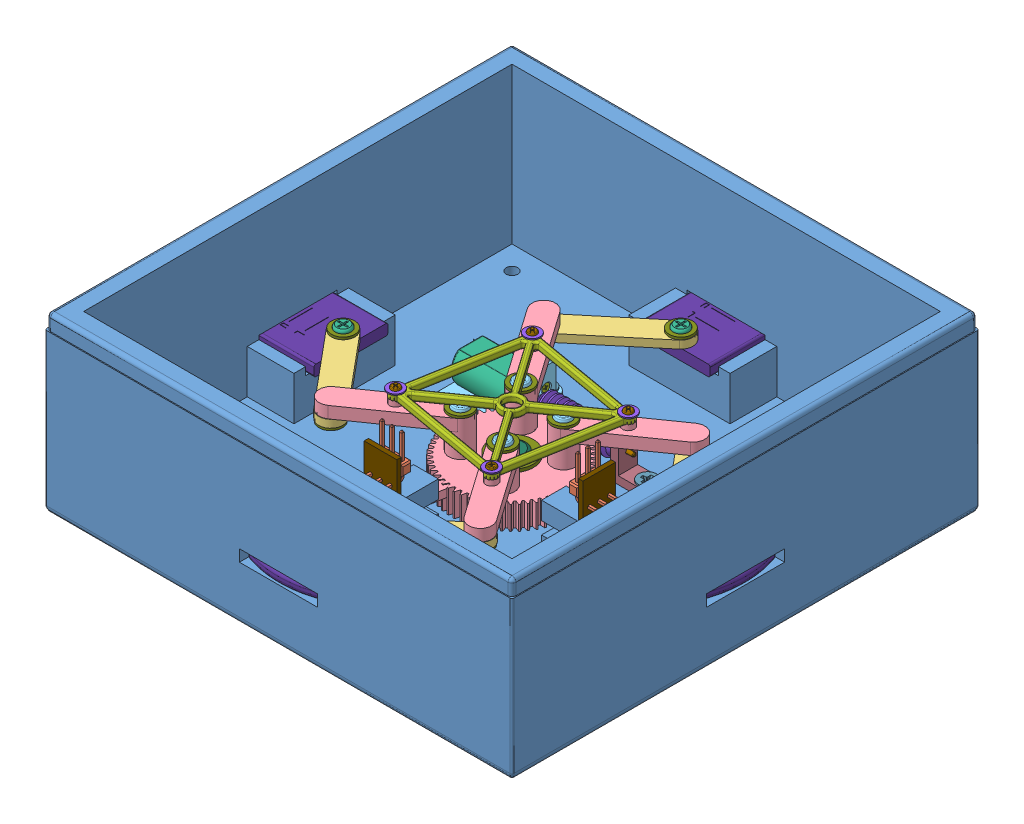
SolidWorks assembly Housing ASSY BOTTOM, configuration Default. Lengths in mm.
Overall size (120.15 45 120.15).
106 component instances, 28 part files, 150 mates.
Components (placement in the parent):
- Housing-Bottom-1: Housing-Bottom [Default] at (58.4375 46.7515 95.6927) size (120 45 120)
- HK 0606-1: HK 0606 [Default] at (58.4375 53.7515 95.6927) x (0 1 0) z (0 0 1) size (6 10 10)
  - HK 0606_PART1-1: HK 0606_PART1 [Default] at origin size (6 10 10)
  - HK 0606_PART2-1: HK 0606_PART2 [Default] at origin size (3.3 1.5 1.5)
  - HK 0606_PART2-2: HK 0606_PART2 [Default] x (1 0 0) z (0 0.707107 0.707107) size (3.3 1.5 1.5)
  - HK 0606_PART2-3: HK 0606_PART2 [Default] x (1 0 0) z (0 1 0) size (3.3 1.5 1.5)
  - HK 0606_PART2-4: HK 0606_PART2 [Default] x (1 0 0) z (0 0.707107 -0.707107) size (3.3 1.5 1.5)
  - HK 0606_PART2-5: HK 0606_PART2 [Default] x (1 0 0) z (0 0 -1) size (3.3 1.5 1.5)
  - HK 0606_PART2-6: HK 0606_PART2 [Default] x (1 0 0) z (0 -0.707107 -0.707107) size (3.3 1.5 1.5)
  - HK 0606_PART2-7: HK 0606_PART2 [Default] x (1 0 0) z (0 -1 0) size (3.3 1.5 1.5)
  - HK 0606_PART2-8: HK 0606_PART2 [Default] x (1 0 0) z (0 -0.707107 0.707107) size (3.3 1.5 1.5)
  - HK 0606_PART3-1: HK 0606_PART3 [Default] at origin
  - HK 0606_PART3-2: HK 0606_PART3 [Default] x (1 0 0) z (0 0.707107 0.707107)
  - HK 0606_PART3-3: HK 0606_PART3 [Default] x (1 0 0) z (0 1 0)
  - HK 0606_PART3-4: HK 0606_PART3 [Default] x (1 0 0) z (0 0.707107 -0.707107)
  - HK 0606_PART3-5: HK 0606_PART3 [Default] x (1 0 0) z (0 0 -1)
  - HK 0606_PART3-6: HK 0606_PART3 [Default] x (1 0 0) z (0 -0.707107 -0.707107)
  - HK 0606_PART3-7: HK 0606_PART3 [Default] x (1 0 0) z (0 -1 0)
  - HK 0606_PART3-8: HK 0606_PART3 [Default] x (1 0 0) z (0 -0.707107 0.707107)
- Center gear-1: Center gear [Default] at (58.4375 59.7515 95.6927) x (-0.818283 0 0.574815) z (0.574815 0 0.818283) size (37.48 15.12 34.22)
- Motor Stand ASSY-2: Motor Stand ASSY [Default] at (30.3718 47.9529 58.991) size (57.7 11.2 22)
  - Motor stand-1: Motor stand [Default] at (14.5557 9.9986 19.1017) x (0 -1 0) z (0 0 1) size (11.2 18.28 22)
  - PKN7EB105C motor-1: PKN7EB105C motor [Default] at (-0.4443 9.9986 19.1017) x (0 0 -1) z (0 -1 0) size (10 25.2 8)
  - SNZF-M1_4-3-TBZ-1: SNZF-M1_4-3-TBZ [Default] at (15.1057 9.9986 15.5017) x (-1 0 0) z (0 -0.147104 0.989121) size (3 2 2)
  - SNZF-M1_4-3-TBZ-2: SNZF-M1_4-3-TBZ [Default] at (15.1057 9.9986 22.7017) x (-1 0 0) z (0 -0.877398 0.479764) size (3 2 2)
  - Worm 21-1: Worm 21 [GearTrax] at (28.0557 9.9986 19.1017) x (0 0 -1) z (1 0 0) size (6 6 21.1)
  - 10mm shaft-1: 10mm shaft [Default] at (32.0557 9.9986 19.1017) x (0 0.407305 0.913292) z (1 0 0) size (1 1 10)
  - W 618_1-1: W 618_1 [Default] at (38.1557 9.9986 19.1017) size (1 3 3)
    - W 618_1_PART1-1: W 618_1_PART1 [Default] at origin size (1 1.55 1.55)
    - W 618_1_PART2-1: W 618_1_PART2 [Default] at origin size (1 3 3)
    - W 618_1_PART3-1: W 618_1_PART3 [Default] at origin size (0.6 0.6 0.6)
    - W 618_1_PART3-2: W 618_1_PART3 [Default] x (1 0 0) z (0 0.866025 0.5) size (0.6 0.6 0.6)
    - W 618_1_PART3-3: W 618_1_PART3 [Default] x (1 0 0) z (0 0.866025 -0.5) size (0.6 0.6 0.6)
    - W 618_1_PART3-4: W 618_1_PART3 [Default] x (1 0 0) z (0 0 -1) size (0.6 0.6 0.6)
    - W 618_1_PART3-5: W 618_1_PART3 [Default] x (1 0 0) z (0 -0.866025 -0.5) size (0.6 0.6 0.6)
    - W 618_1_PART3-6: W 618_1_PART3 [Default] x (1 0 0) z (0 -0.866025 0.5) size (0.6 0.6 0.6)
  - Bearing stand-2: Bearing stand [Default] at (40.2557 9.9986 19.1017) x (0 0 1) z (-1 0 0) size (5 8.7 17)
- countersunk flat head cross recess screw_iso-1: countersunk flat head cross recess screw_iso [ISO 7046-1 - M2.5 x 4 - Z - 4S] at (41.5775 53.9515 86.0927) x (0 -1 0) z (0.986483 0 -0.163866) size (4 4.7 4.7)
- countersunk flat head cross recess screw_iso-2: countersunk flat head cross recess screw_iso [ISO 7046-1 - M2.5 x 4 - Z - 4S] at (75.6275 54.2515 78.0927) x (0 -1 0) z (0.994864 0 -0.10122) size (4 4.7 4.7)
- countersunk flat head cross recess screw_iso-3: countersunk flat head cross recess screw_iso [ISO 7046-1 - M2.5 x 4 - Z - 4S] at (41.5775 53.9515 70.0927) x (0 -1 0) z (0.998701 0 -0.050963) size (4 4.7 4.7)
- countersunk flat head cross recess screw_iso-4: countersunk flat head cross recess screw_iso [ISO 7046-1 - M2.5 x 4 - Z - 4S] at (32.4775 53.9515 86.0927) x (0 -1 0) z (0 0 1) size (4 4.7 4.7)
- countersunk flat head cross recess screw_iso-5: countersunk flat head cross recess screw_iso [ISO 7046-1 - M2.5 x 4 - Z - 4S] at (32.4775 53.9515 70.0927) x (0 -1 0) z (-0.882562 0 0.470195) size (4 4.7 4.7)
- countersunk flat head cross recess screw_iso-6: countersunk flat head cross recess screw_iso [ISO 7046-1 - M2.5 x 4 - Z - 4S] at (80.6275 54.2515 78.0927) x (0 -1 0) z (0 0 1) size (4 4.7 4.7)
- SEQ-M3-6-TZB-1: SEQ-M3-6-TZB [Default] at (58.4375 60.5515 95.6927) x (0 -1 0) z (0 0 1) size (6.8 7 7)
- plain washer 10673 type snl_iso-4: plain washer 10673 type snl_iso [ISO 10673-3.2-L] at (58.4375 59.7515 95.6927) x (0 1 0) z (0.0196 0 -0.999808) size (0.8 11 11)
- Locking insert-1: Locking insert [Default] at (0.1058 63.8715 95.6927) x (1 0 0) z (0 -1 0) size (18.71 19 4.86)
- Locking insert-2: Locking insert [Default] at (58.4375 63.8715 37.3608) x (0 0 1) z (0 -1 0) size (18.71 19 4.86)
- Locking insert-3: Locking insert [Default] at (58.4375 63.8715 154.0246) x (0 0 -1) z (0 -1 0) size (18.71 19 4.86)
- Locking insert-4: Locking insert [Default] at (116.7696 63.8715 95.6927) x (-1 0 0) z (0 -1 0) size (18.71 19 4.86)
- LightInterrupter ASSY-1: LightInterrupter ASSY [Default] at (106.8605 54.653 115.9706) x (0 1 0) z (-1 0 0) size (27.79 23.15 13.77)
  - light interrupter-1: light interrupter [Default] at (-28.3605 -96.0125 19.17) size (23.5 8.4 2.42)
  - OPB840L51-1: OPB840L51 [Default] at (3.5735 12.3185 19.17) x (1 0 0) z (0 -1 0) size (12.95 13.04 23.15)
  - Pin Header 1x3 TH Angle Pitch 2.54mm-1: Pin Header 1x3 TH Angle Pitch 2.54mm [Default] at (14.0957 9.7707 19.1411) x (0 1 0) z (0 0 1) size (7.63 11.11 6.29)
- Lock lever 25-1: Lock lever 25 [Default] at (48.8375 63.8715 60.3329) x (-0.768003 0 0.640446) z (-0.640446 0 -0.768003) size (31.2 2 6.2)
- Lock lever 25-2: Lock lever 25 [Default] at (93.7975 63.8715 86.0927) x (-0.640452 0 -0.767999) z (0.767999 0 -0.640452) size (31.2 2 6.2)
- Lock lever 25-3: Lock lever 25 [Default] at (23.0778 63.8715 105.2928) x (-0.640443 0 -0.768006) z (0.768006 0 -0.640443) size (31.2 2 6.2)
- Lock lever 25-4: Lock lever 25 [Default] at (68.0376 63.8715 131.0525) x (0.768001 0 -0.640448) z (0.640448 0 0.768001) size (31.2 2 6.2)
- LightInterrupter ASSY-2: LightInterrupter ASSY [Default] at (43.6894 54.653 145.0604) x (0 1 0) z (0 0 -1) size (27.79 23.15 13.77)
  - light interrupter-1: light interrupter [Default] at (-28.3605 -96.0125 19.17) size (23.5 8.4 2.42)
  - OPB840L51-1: OPB840L51 [Default] at (3.5735 12.3185 19.17) x (1 0 0) z (0 -1 0) size (12.95 13.04 23.15)
  - Pin Header 1x3 TH Angle Pitch 2.54mm-1: Pin Header 1x3 TH Angle Pitch 2.54mm [Default] at (14.0957 9.7707 19.1411) x (0 1 0) z (0 0 1) size (7.63 11.11 6.29)
- Lock lever 23-1: Lock lever 23 [Default] at (40.8736 65.8715 108.0231) x (0.818582 0 -0.57439) z (0.57439 0 0.818582) size (29.92 12.12 6)
- Lock lever 23-2: Lock lever 23 [Default] at (70.7679 65.8715 113.2567) x (-0.574385 0 -0.818585) z (0.818585 0 -0.574385) size (29.92 12.12 6)
- Lock lever 23-3: Lock lever 23 [Default] at (76.0015 65.8715 83.3623) x (-0.818587 0 0.574382) z (-0.574382 0 -0.818587) size (29.92 12.12 6)
- Lock lever 23-4: Lock lever 23 [Default] at (46.1071 65.8715 78.1287) x (0.574387 0 0.818584) z (-0.818584 0 0.574387) size (29.92 12.12 6)
- plain washer 10673 type snl_iso-6: plain washer 10673 type snl_iso [ISO 10673-2.75-S] at (66.2112 68.8715 90.232) x (0 1 0) z (0 0 -1) size (0.6 6 6)
- plain washer 10673 type snl_iso-7: plain washer 10673 type snl_iso [ISO 10673-2.75-S] at (63.8983 68.8715 103.4664) x (0 1 0) z (0 0 -1) size (0.6 6 6)
- plain washer 10673 type snl_iso-8: plain washer 10673 type snl_iso [ISO 10673-2.75-S] at (50.6639 68.8715 101.1534) x (0 1 0) z (0 0 1) size (0.6 6 6)
- plain washer 10673 type snl_iso-9: plain washer 10673 type snl_iso [ISO 10673-2.75-S] at (52.9768 68.8715 87.919) x (0 1 0) z (0 0 1) size (0.6 6 6)
- SNZS-M2_5-6-1: SNZS-M2_5-6 [Default] at (50.6639 69.4715 101.1534) x (0 -1 0) z (0 0 1) size (6.8 4 4)
- SNZS-M2_5-6-2: SNZS-M2_5-6 [Default] at (63.8983 69.4715 103.4664) x (0 -1 0) z (0 0 1) size (6.8 4 4)
- SNZS-M2_5-6-3: SNZS-M2_5-6 [Default] at (52.9768 69.4715 87.919) x (0 -1 0) z (0 0 1) size (6.8 4 4)
- SNZS-M2_5-6-4: SNZS-M2_5-6 [Default] at (66.2112 69.4715 90.232) x (0 -1 0) z (0 0 1) size (6.8 4 4)
- plain washer 10673 type snl_iso-11: plain washer 10673 type snl_iso [ISO 10673-2.75-S] at (39.2375 63.8715 68.3385) x (0 -1 0) z (-0.982657 0 -0.185434) size (0.6 6 6)
- plain washer 10673 type snl_iso-13: plain washer 10673 type snl_iso [ISO 10673-2.75-S] at (77.6376 63.8715 123.0469) x (0 -1 0) z (-0.441249 0 -0.897385) size (0.6 6 6)
- plain washer 10673 type snl_iso-14: plain washer 10673 type snl_iso [ISO 10673-2.75-S] at (31.0834 63.8715 114.8928) x (0 -1 0) z (0 0 1) size (0.6 6 6)
- plain washer 10673 type snl_iso-16: plain washer 10673 type snl_iso [ISO 10673-2.75-S] at (85.7918 63.8715 76.4927) x (0 -1 0) z (0.546944 0 -0.837169) size (0.6 6 6)
- SNZS-M2_5-3-1: SNZS-M2_5-3 [Default] at (77.6376 63.2715 123.0469) x (0 1 0) z (0 0 1) size (3.8 4.02 4.02)
- SNZS-M2_5-3-2: SNZS-M2_5-3 [Default] at (31.0834 63.2715 114.8928) x (0 1 0) z (0 0 1) size (3.8 4.02 4.02)
- SNZS-M2_5-3-3: SNZS-M2_5-3 [Default] at (85.7918 63.2715 76.4927) x (0 1 0) z (0 0 1) size (3.8 4.02 4.02)
- SNZS-M2_5-3-4: SNZS-M2_5-3 [Default] at (39.2375 63.2715 68.3385) x (0 1 0) z (0 0 1) size (3.8 4.02 4.02)
- plain washer 10673 type snl_iso-18: plain washer 10673 type snl_iso [ISO 10673-2.75-S] at (58.4375 65.8715 52.3273) x (0 1 0) z (0 0 1) size (0.6 6 6)
- plain washer 10673 type snl_iso-19: plain washer 10673 type snl_iso [ISO 10673-2.75-S] at (15.0723 65.8715 95.6927) x (0 1 0) z (0 0 1) size (0.6 6 6)
- plain washer 10673 type snl_iso-20: plain washer 10673 type snl_iso [ISO 10673-2.75-S] at (58.4375 65.8715 139.0582) x (0 1 0) z (0 0 1) size (0.6 6 6)
- plain washer 10673 type snl_iso-21: plain washer 10673 type snl_iso [ISO 10673-2.75-S] at (101.8031 65.8715 95.6927) x (0 1 0) z (-0.915769 0 0.401704) size (0.6 6 6)
- SNZS-M2_5-3-5: SNZS-M2_5-3 [Default] at (15.0723 66.4715 95.6927) x (0 -1 0) z (0 0 1) size (3.8 4.02 4.02)
- SNZS-M2_5-3-6: SNZS-M2_5-3 [Default] at (58.4375 66.4715 52.3273) x (0 -1 0) z (0 0 1) size (3.8 4.02 4.02)
- SNZS-M2_5-3-7: SNZS-M2_5-3 [Default] at (101.8031 66.4715 95.6927) x (0 -1 0) z (0 0 1) size (3.8 4.02 4.02)
- SNZS-M2_5-3-8: SNZS-M2_5-3 [Default] at (58.4375 66.4715 139.0582) x (0 -1 0) z (0 0 1) size (3.8 4.02 4.02)
- 23 lever spacer-2: 23 lever spacer [Default] at (58.4376 69.8715 95.6927) x (0.985019 0 0.172446) z (-0.172446 0 0.985019) size (33.35 2.06 33.35)
- plain washer normal grade a_iso-2: plain washer normal grade a_iso [Washer ISO 7089 - 1.6] at (46.1071 71.8715 78.1287) x (0 -1 0) z (0.996822 0 0.079656) size (0.3 4 4)
- plain washer normal grade a_iso-3: plain washer normal grade a_iso [Washer ISO 7089 - 1.6] at (40.873 71.8715 108.0235) x (0 -1 0) z (0.445519 0 -0.895272) size (0.3 4 4)
- plain washer normal grade a_iso-4: plain washer normal grade a_iso [Washer ISO 7089 - 1.6] at (70.7679 71.8715 113.2567) x (0 -1 0) z (0 0 1) size (0.3 4 4)
- plain washer normal grade a_iso-5: plain washer normal grade a_iso [Washer ISO 7089 - 1.6] at (76.0015 71.8715 83.3623) x (0 -1 0) z (0 0 1) size (0.3 4 4)
- SNZS-M1_6-3-5: SNZS-M1_6-3 [Default] at (76.0015 72.1715 83.3623) x (0 -1 0) z (0 0 1) size (3.5 2.3 2.3)
- SNZS-M1_6-3-6: SNZS-M1_6-3 [Default] at (70.7679 72.1715 113.2567) x (0 -1 0) z (-0.649279 0 0.76055) size (3.5 2.3 2.3)
- SNZS-M1_6-3-7: SNZS-M1_6-3 [Default] at (46.1071 72.1715 78.1287) x (0 -1 0) z (0 0 1) size (3.5 2.3 2.3)
- SNZS-M1_6-3-8: SNZS-M1_6-3 [Default] at (40.8736 72.1715 108.0231) x (0 -1 0) z (0 0 1) size (3.5 2.3 2.3)
- plain washer normal grade a_iso-10: plain washer normal grade a_iso [Washer ISO 7089 - 1.6] at (81.7255 53.7815 110.7622) x (0 -1 0) z (0.705829 0 0.708382) size (0.3 4 4)
- plain washer normal grade a_iso-11: plain washer normal grade a_iso [Washer ISO 7089 - 1.6] at (48.8979 53.7815 119.9254) x (0 -1 0) z (0 0 1) size (0.3 4 4)
- plain washer normal grade a_iso-12: plain washer normal grade a_iso [Washer ISO 7089 - 1.6] at (81.7255 53.7815 96.546) x (0 -1 0) z (0 0 1) size (0.3 4 4)
- plain washer normal grade a_iso-13: plain washer normal grade a_iso [Washer ISO 7089 - 1.6] at (63.114 53.7815 119.9254) x (0 -1 0) z (0 0 1) size (0.3 4 4)
- SNZS-M1_6-3-9: SNZS-M1_6-3 [Default] at (48.8979 54.0815 119.9254) x (0 -1 0) z (1 0 0) size (3.5 2.3 2.3)
- SNZS-M1_6-3-10: SNZS-M1_6-3 [Default] at (81.7255 54.0815 96.546) x (0 -1 0) z (0 0 1) size (3.5 2.3 2.3)
- SNZS-M1_6-3-11: SNZS-M1_6-3 [Default] at (81.7255 54.0815 110.7622) x (0 -1 0) z (0 0 1) size (3.5 2.3 2.3)
- SNZS-M1_6-3-12: SNZS-M1_6-3 [Default] at (63.114 54.0815 119.9254) x (0 -1 0) z (0 0 1) size (3.5 2.3 2.3)
Mates (geometry in assembly coordinates):
- Concentric1: concentric anti-aligned: circle of Housing-Bottom-1; circle of HK 0606-1/HK 0606_PART1-1
- Coincident3: coincident anti-aligned: plane of Housing-Bottom-1 through (58.4375 53.7515 95.6927) normal (0 1 0); plane of HK 0606-1/HK 0606_PART1-1 through (53.8375 53.7515 95.6927) normal (0 -1 0)
- Concentric2: concentric aligned: circle of HK 0606-1/HK 0606_PART1-1; circle of Center gear-1
- Coincident4: coincident anti-aligned: plane of Housing-Bottom-1 through (58.4375 53.7515 95.6927) normal (0 1 0); plane of Center gear-1 through (57.2231 53.7515 88.7504) normal (0 -1 0)
- Coincident5: coincident anti-aligned: plane of Housing-Bottom-1 through (58.4375 51.7515 95.6927) normal (0 1 0); plane of Motor Stand ASSY-2/Motor stand-1 through (32.4775 51.7515 70.0927) normal (0 -1 0)
- Concentric4: concentric anti-aligned: circle of Housing-Bottom-1; circle of Motor Stand ASSY-2/Motor stand-1
- Concentric5: concentric anti-aligned: circle of Housing-Bottom-1; circle of Motor Stand ASSY-2/Motor stand-1
- Concentric6: concentric aligned: circle of Housing-Bottom-1; circle of countersunk flat head cross recess screw_iso-6
- Coincident6: coincident aligned: cone of Motor Stand ASSY-2/Bearing stand-2 through (80.6275 52.7515 78.0927) axis (0 -1 0); cylinder of countersunk flat head cross recess screw_iso-6 through (80.6275 53.8515 78.0927) axis (0 -1 0) radius 785.3982
- Concentric7: concentric aligned: circle of Motor Stand ASSY-2/Bearing stand-2; cylinder of countersunk flat head cross recess screw_iso-2 through (75.6275 60.6015 78.0927) axis (0 1 0) radius 1.25
- Coincident9: coincident aligned: cylinder of Motor Stand ASSY-2/Bearing stand-2 through (75.6275 52.7515 78.0927) axis (0 -1 0) radius 785.3982; cylinder of countersunk flat head cross recess screw_iso-2 through (75.6275 53.8515 78.0927) axis (0 -1 0) radius 785.3982
- Concentric8: concentric anti-aligned: circle of Housing-Bottom-1; cylinder of countersunk flat head cross recess screw_iso-4 through (32.4775 49.9515 86.0927) axis (0 -1 0) radius 959.9311
- Coincident11: coincident aligned: cylinder of Motor Stand ASSY-2/Motor stand-1 through (32.4775 52.4515 86.0927) axis (0 -1 0) radius 785.3982; cylinder of countersunk flat head cross recess screw_iso-4 through (32.4775 53.5515 86.0927) axis (0 -1 0) radius 785.3982
- Concentric9: concentric aligned: circle of Housing-Bottom-1; circle of countersunk flat head cross recess screw_iso-5
- Coincident12: coincident aligned: cylinder of Motor Stand ASSY-2/Motor stand-1 through (32.4775 52.9515 70.0927) axis (0 -1 0) radius 785.3982; cylinder of countersunk flat head cross recess screw_iso-5 through (32.4775 53.5515 70.0927) axis (0 -1 0) radius 785.3982
- Concentric10: concentric aligned: circle of Housing-Bottom-1; circle of countersunk flat head cross recess screw_iso-3
- Coincident13: coincident aligned: cylinder of Motor Stand ASSY-2/Motor stand-1 through (41.5775 52.9515 70.0927) axis (0 -1 0) radius 785.3982; cylinder of countersunk flat head cross recess screw_iso-3 through (41.5775 53.5515 70.0927) axis (0 -1 0) radius 785.3982
- Concentric11: concentric aligned: circle of Housing-Bottom-1; circle of countersunk flat head cross recess screw_iso-1
- Coincident14: coincident aligned: cylinder of Motor Stand ASSY-2/Motor stand-1 through (41.5775 52.4515 86.0927) axis (0 -1 0) radius 785.3982; cylinder of countersunk flat head cross recess screw_iso-1 through (41.5775 53.5515 86.0927) axis (0 -1 0) radius 785.3982
- Concentric12: concentric anti-aligned: cylinder of Housing-Bottom-1 through (58.4375 59.7515 95.6927) axis (0 -1 0) radius 3; cylinder of ? through (58.4375 87.5515 95.6927) axis (0 1 0) radius 2.8
- Coincident15: coincident: plane of Housing-Bottom-1 through (58.4375 59.7515 95.6927) normal (0 1 0); plane of ? through (59.9375 59.7515 95.6927) normal (0 -1 0)
- Concentric14: concentric aligned: cylinder of Housing-Bottom-1 through (58.4375 59.7515 95.6927) axis (0 -1 0) radius 3; cylinder of ? through (58.4375 60.5515 95.6927) axis (0 -1 0) radius 1.6
- Coincident19: coincident anti-aligned: plane of Housing-Bottom-1 through (58.4375 59.7515 95.6927) normal (0 1 0); plane of plain washer 10673 type snl_iso-4 through (58.4375 59.7515 95.6927) normal (0 -1 0)
- Concentric15: concentric anti-aligned: cylinder of Housing-Bottom-1 through (58.4375 51.7515 95.6927) axis (0 1 0) radius 1.2; cylinder of plain washer 10673 type snl_iso-4 through (58.4375 60.5515 95.6927) axis (0 -1 0) radius 1.6
- Coincident20: coincident anti-aligned: plane of Housing-Bottom-1 through (58.4375 59.7515 95.6927) normal (0 1 0); plane of plain washer 10673 type snl_iso-4 through (58.4375 59.7515 95.6927) normal (0 -1 0)
- Concentric16: concentric aligned: circle of SEQ-M3-6-TZB-1; circle of plain washer 10673 type snl_iso-4
- Coincident21: coincident aligned: circle of SEQ-M3-6-TZB-1; plane of plain washer 10673 type snl_iso-4 through (58.4375 60.5515 95.6927) normal (0 1 0)
- Distance3: distance = 0.1 mm anti-aligned: plane of Locking insert-3 through (58.4375 63.8715 129.0246) normal (0 1 0); plane of Housing-Bottom-1 through (48.4375 63.9715 155.6927) normal (0 -1 0)
- Distance5: distance = 0.5 mm anti-aligned: plane of Locking insert-3 through (67.9375 61.0715 137.0582) normal (1 0 0); plane of Housing-Bottom-1 through (68.4375 63.9715 155.6927) normal (-1 0 0)
- Distance6: distance = 0.5 mm anti-aligned: plane of Housing-Bottom-1 through (-1.5625 63.9715 105.6927) normal (0 0 -1); plane of Locking insert-1 through (17.0723 61.0715 105.1927) normal (0 0 1)
- Distance7: distance = 0.1 mm anti-aligned: plane of Housing-Bottom-1 through (-1.5625 60.9715 105.6927) normal (0 1 0); plane of Locking insert-1 through (25.1058 61.0715 95.6927) normal (0 -1 0)
- Distance8: distance = 0.5 mm anti-aligned: plane of Locking insert-2 through (48.9375 61.0715 54.3273) normal (-1 0 0); plane of Housing-Bottom-1 through (48.4375 63.9715 35.6927) normal (1 0 0)
- Distance9: distance = 0.1 mm anti-aligned: plane of Locking insert-2 through (58.4375 61.0715 62.3608) normal (0 -1 0); plane of Housing-Bottom-1 through (48.4375 60.9715 35.6927) normal (0 1 0)
- Distance10: distance = 0.1 mm anti-aligned: plane of Locking insert-4 through (91.7696 61.0715 95.6927) normal (0 -1 0); plane of Housing-Bottom-1 through (118.4375 60.9715 85.6927) normal (0 1 0)
- Distance11: distance = 0.5 mm anti-aligned: plane of Locking insert-4 through (99.8031 61.0715 86.1927) normal (0 0 -1); plane of Housing-Bottom-1 through (118.4375 63.9715 85.6927) normal (0 0 1)
- Concentric18: concentric aligned: circle of Locking insert-3; circle of Lock lever 25-4
- Concentric19: concentric aligned: circle of Locking insert-4; circle of Lock lever 25-2
- Concentric20: concentric aligned: circle of Locking insert-2; circle of Lock lever 25-1
- Concentric21: concentric aligned: circle of Locking insert-1; circle of Lock lever 25-3
- Coincident38: coincident anti-aligned: plane of Locking insert-2 through (58.4375 63.8715 62.3608) normal (0 1 0); plane of Lock lever 25-1 through (58.4375 63.8715 52.3273) normal (0 -1 0)
- Coincident39: coincident anti-aligned: plane of Locking insert-1 through (25.1058 63.8715 95.6927) normal (0 1 0); plane of Lock lever 25-3 through (31.0834 63.8715 114.8928) normal (0 -1 0)
- Coincident40: coincident anti-aligned: plane of Locking insert-3 through (58.4375 63.8715 129.0246) normal (0 1 0); plane of Lock lever 25-4 through (58.4375 63.8715 139.0582) normal (0 -1 0)
- Coincident41: coincident anti-aligned: plane of Locking insert-4 through (91.7696 63.8715 95.6927) normal (0 1 0); plane of Lock lever 25-2 through (101.8031 63.8715 95.6927) normal (0 -1 0)
- Concentric22: concentric anti-aligned: circle of Center gear-1; circle of Lock lever 23-1
- Concentric23: concentric anti-aligned: circle of Lock lever 25-3; circle of Lock lever 23-1
- Coincident43: coincident anti-aligned: plane of Lock lever 25-3 through (31.0834 65.8715 114.8928) normal (0 1 0); plane of Lock lever 23-1 through (31.0834 65.8715 114.8928) normal (0 -1 0)
- Concentric24: concentric anti-aligned: circle of Center gear-1; circle of Lock lever 23-3
- Concentric25: concentric anti-aligned: circle of Lock lever 25-2; circle of Lock lever 23-3
- Coincident45: coincident anti-aligned: plane of Lock lever 25-2 through (101.8031 65.8715 95.6927) normal (0 1 0); plane of Lock lever 23-3 through (85.7918 65.8715 76.4927) normal (0 -1 0)
- Concentric26: concentric anti-aligned: circle of Lock lever 25-4; circle of Lock lever 23-2
- Concentric27: concentric anti-aligned: circle of Center gear-1; circle of Lock lever 23-2
- Coincident46: coincident anti-aligned: plane of Lock lever 25-4 through (58.4375 65.8715 139.0582) normal (0 1 0); plane of Lock lever 23-2 through (77.6376 65.8715 123.0469) normal (0 -1 0)
- Concentric28: concentric anti-aligned: circle of Lock lever 25-1; circle of Lock lever 23-4
- Concentric29: concentric anti-aligned: circle of Center gear-1; circle of Lock lever 23-4
- Coincident47: coincident anti-aligned: plane of Lock lever 25-1 through (58.4375 65.8715 52.3273) normal (0 1 0); plane of Lock lever 23-4 through (39.2375 65.8715 68.3385) normal (0 -1 0)
- Concentric30: concentric aligned: circle of Lock lever 23-2; circle of ?
- Concentric31: concentric aligned: circle of Lock lever 23-1; circle of ?
- Concentric32: concentric aligned: circle of Lock lever 23-3; circle of ?
- Concentric33: concentric aligned: circle of Lock lever 23-4; circle of ?
- Concentric34: concentric anti-aligned: cylinder of Center gear-1 through (66.2112 60.8715 90.232) axis (0 1 0) radius 1.1; cylinder of plain washer 10673 type snl_iso-6 through (66.2112 69.4715 90.232) axis (0 -1 0) radius 1.375
- Coincident54: coincident anti-aligned: plane of Center gear-1 through (66.2112 68.8715 90.232) normal (0 1 0); plane of plain washer 10673 type snl_iso-6 through (66.2112 68.8715 90.232) normal (0 -1 0)
- Concentric35: concentric aligned: cylinder of Lock lever 23-2 through (63.8983 68.8715 103.4664) axis (0 -1 0) radius 2.1; cylinder of plain washer 10673 type snl_iso-7 through (63.8983 69.4715 103.4664) axis (0 -1 0) radius 1.375
- Coincident55: coincident anti-aligned: plane of Lock lever 23-2 through (77.6376 68.8715 123.0469) normal (0 1 0); plane of plain washer 10673 type snl_iso-7 through (63.8983 68.8715 103.4664) normal (0 -1 0)
- Concentric36: concentric anti-aligned: cylinder of Center gear-1 through (50.6639 60.8715 101.1534) axis (0 1 0) radius 1.1; cylinder of plain washer 10673 type snl_iso-8 through (50.6639 69.4715 101.1534) axis (0 -1 0) radius 1.375
- Coincident56: coincident anti-aligned: plane of Center gear-1 through (50.6639 68.8715 101.1534) normal (0 1 0); plane of plain washer 10673 type snl_iso-8 through (50.6639 68.8715 101.1534) normal (0 -1 0)
- Concentric37: concentric anti-aligned: cylinder of Center gear-1 through (52.9768 60.8715 87.919) axis (0 1 0) radius 1.1; cylinder of plain washer 10673 type snl_iso-9 through (52.9768 69.4715 87.919) axis (0 -1 0) radius 1.375
- Coincident57: coincident anti-aligned: plane of Center gear-1 through (52.9768 68.8715 87.919) normal (0 1 0); plane of plain washer 10673 type snl_iso-9 through (52.9768 68.8715 87.919) normal (0 -1 0)
- Concentric38: concentric aligned: circle of Center gear-1; circle of SNZS-M2_5-6-4
- Coincident58: coincident anti-aligned: plane of plain washer 10673 type snl_iso-6 through (66.2112 69.4715 90.232) normal (0 1 0); plane of SNZS-M2_5-6-4 through (68.2112 69.4715 90.232) normal (0 -1 0)
- Concentric39: concentric aligned: circle of Center gear-1; circle of SNZS-M2_5-6-2
- Coincident59: coincident anti-aligned: plane of plain washer 10673 type snl_iso-7 through (63.8983 69.4715 103.4664) normal (0 1 0); plane of SNZS-M2_5-6-2 through (65.8983 69.4715 103.4664) normal (0 -1 0)
- Concentric40: concentric aligned: circle of Center gear-1; circle of SNZS-M2_5-6-1
- Coincident60: coincident anti-aligned: plane of plain washer 10673 type snl_iso-8 through (50.6639 69.4715 101.1534) normal (0 1 0); plane of SNZS-M2_5-6-1 through (52.6639 69.4715 101.1534) normal (0 -1 0)
- Concentric41: concentric aligned: circle of Center gear-1; circle of SNZS-M2_5-6-3
- Coincident61: coincident anti-aligned: plane of plain washer 10673 type snl_iso-9 through (52.9768 69.4715 87.919) normal (0 1 0); plane of SNZS-M2_5-6-3 through (54.9768 69.4715 87.919) normal (0 -1 0)
- Concentric42: concentric anti-aligned: cylinder of Lock lever 23-4 through (39.2375 67.3715 68.3385) axis (0 -1 0) radius 1.1; cylinder of plain washer 10673 type snl_iso-11 through (39.2375 63.2715 68.3385) axis (0 1 0) radius 1.375
- Coincident62: coincident anti-aligned: plane of Lock lever 23-4 through (39.2375 63.8715 68.3385) normal (0 -1 0); plane of plain washer 10673 type snl_iso-11 through (39.2375 63.8715 68.3385) normal (0 1 0)
- Concentric43: concentric anti-aligned: cylinder of Lock lever 23-2 through (77.6376 67.3715 123.0469) axis (0 -1 0) radius 1.1; cylinder of plain washer 10673 type snl_iso-13 through (77.6376 63.2715 123.0469) axis (0 1 0) radius 1.375
- Coincident63: coincident anti-aligned: plane of Lock lever 23-2 through (77.6376 63.8715 123.0469) normal (0 -1 0); plane of plain washer 10673 type snl_iso-13 through (77.6376 63.8715 123.0469) normal (0 1 0)
- Concentric44: concentric anti-aligned: cylinder of Lock lever 23-1 through (31.0834 67.3715 114.8928) axis (0 -1 0) radius 1.1; cylinder of plain washer 10673 type snl_iso-14 through (31.0834 63.2715 114.8928) axis (0 1 0) radius 1.375
- Coincident64: coincident anti-aligned: plane of Lock lever 23-1 through (31.0834 63.8715 114.8928) normal (0 -1 0); plane of plain washer 10673 type snl_iso-14 through (31.0834 63.8715 114.8928) normal (0 1 0)
- Concentric45: concentric anti-aligned: cylinder of Lock lever 23-3 through (85.7918 67.3715 76.4927) axis (0 -1 0) radius 1.1; cylinder of plain washer 10673 type snl_iso-16 through (85.7918 63.2715 76.4927) axis (0 1 0) radius 1.375
- Coincident65: coincident anti-aligned: plane of Lock lever 23-3 through (85.7918 63.8715 76.4927) normal (0 -1 0); plane of plain washer 10673 type snl_iso-16 through (85.7918 63.8715 76.4927) normal (0 1 0)
- Concentric46: concentric aligned: circle of Lock lever 23-4; circle of SNZS-M2_5-3-4
- Coincident66: coincident anti-aligned: plane of plain washer 10673 type snl_iso-11 through (39.2375 63.2715 68.3385) normal (0 -1 0); plane of SNZS-M2_5-3-4 through (37.2375 63.2715 68.3385) normal (0 1 0)
- Concentric47: concentric aligned: circle of Lock lever 23-1; circle of SNZS-M2_5-3-2
- Coincident67: coincident anti-aligned: plane of plain washer 10673 type snl_iso-14 through (31.0834 63.2715 114.8928) normal (0 -1 0); plane of SNZS-M2_5-3-2 through (29.0834 63.2715 114.8928) normal (0 1 0)
- Concentric48: concentric aligned: circle of Lock lever 23-2; circle of SNZS-M2_5-3-1
- Coincident68: coincident anti-aligned: plane of plain washer 10673 type snl_iso-13 through (77.6376 63.2715 123.0469) normal (0 -1 0); plane of SNZS-M2_5-3-1 through (75.6376 63.2715 123.0469) normal (0 1 0)
- Concentric49: concentric aligned: circle of Lock lever 23-3; circle of SNZS-M2_5-3-3
- Coincident69: coincident anti-aligned: plane of plain washer 10673 type snl_iso-16 through (85.7918 63.2715 76.4927) normal (0 -1 0); plane of SNZS-M2_5-3-3 through (83.7918 63.2715 76.4927) normal (0 1 0)
- Concentric50: concentric anti-aligned: cylinder of Locking insert-2 through (58.4375 62.3715 52.3273) axis (0 1 0) radius 1.1; cylinder of plain washer 10673 type snl_iso-18 through (58.4375 66.4715 52.3273) axis (0 -1 0) radius 1.375
- Coincident70: coincident anti-aligned: plane of Locking insert-2 through (58.4375 65.8715 52.3273) normal (0 1 0); plane of plain washer 10673 type snl_iso-18 through (58.4375 65.8715 52.3273) normal (0 -1 0)
- Concentric51: concentric aligned: cylinder of Locking insert-1 through (15.0723 65.8715 95.6927) axis (0 -1 0) radius 2; cylinder of plain washer 10673 type snl_iso-19 through (15.0723 66.4715 95.6927) axis (0 -1 0) radius 1.375
- Coincident71: coincident anti-aligned: plane of Locking insert-1 through (15.0723 65.8715 95.6927) normal (0 1 0); plane of plain washer 10673 type snl_iso-19 through (15.0723 65.8715 95.6927) normal (0 -1 0)
- Concentric52: concentric aligned: cylinder of Lock lever 25-4 through (58.4375 65.8715 139.0582) axis (0 -1 0) radius 2.1; cylinder of plain washer 10673 type snl_iso-20 through (58.4375 66.4715 139.0582) axis (0 -1 0) radius 1.375
- Coincident72: coincident anti-aligned: plane of Lock lever 25-4 through (58.4375 65.8715 139.0582) normal (0 1 0); plane of plain washer 10673 type snl_iso-20 through (58.4375 65.8715 139.0582) normal (0 -1 0)
- Concentric53: concentric aligned: cylinder of Lock lever 25-2 through (101.8031 65.8715 95.6927) axis (0 -1 0) radius 2.1; cylinder of plain washer 10673 type snl_iso-21 through (101.8031 66.4715 95.6927) axis (0 -1 0) radius 1.375
- Coincident73: coincident anti-aligned: plane of Lock lever 25-2 through (101.8031 65.8715 95.6927) normal (0 1 0); plane of plain washer 10673 type snl_iso-21 through (101.8031 65.8715 95.6927) normal (0 -1 0)
- Concentric54: concentric aligned: circle of Locking insert-2; circle of SNZS-M2_5-3-6
- Coincident74: coincident anti-aligned: plane of plain washer 10673 type snl_iso-18 through (58.4375 66.4715 52.3273) normal (0 1 0); plane of SNZS-M2_5-3-6 through (60.4375 66.4715 52.3273) normal (0 -1 0)
- Concentric55: concentric aligned: circle of Locking insert-1; circle of SNZS-M2_5-3-5
- Coincident75: coincident anti-aligned: plane of plain washer 10673 type snl_iso-19 through (15.0723 66.4715 95.6927) normal (0 1 0); plane of SNZS-M2_5-3-5 through (17.0723 66.4715 95.6927) normal (0 -1 0)
- Concentric56: concentric aligned: circle of Locking insert-3; circle of SNZS-M2_5-3-8
- Coincident76: coincident anti-aligned: plane of plain washer 10673 type snl_iso-20 through (58.4375 66.4715 139.0582) normal (0 1 0); plane of SNZS-M2_5-3-8 through (60.4375 66.4715 139.0582) normal (0 -1 0)
- Concentric57: concentric aligned: circle of Locking insert-4; circle of SNZS-M2_5-3-7
- Coincident77: coincident anti-aligned: plane of plain washer 10673 type snl_iso-21 through (101.8031 66.4715 95.6927) normal (0 1 0); plane of SNZS-M2_5-3-7 through (103.8031 66.4715 95.6927) normal (0 -1 0)
- Concentric58: concentric aligned: circle of Lock lever 23-2; circle of 23 lever spacer-2
- Concentric59: concentric aligned: circle of Lock lever 23-3; circle of 23 lever spacer-2
- Concentric60: concentric aligned: circle of Lock lever 23-4; circle of 23 lever spacer-2
- Concentric63: concentric aligned: circle of Lock lever 23-1; circle of 23 lever spacer-2
- Coincident78: coincident anti-aligned: plane of Lock lever 23-3 through (76.0015 70.8715 83.3623) normal (0 1 0); plane of 23 lever spacer-2 through (76.0021 70.8715 83.362) normal (0 -1 0)
- Concentric64: concentric aligned: cylinder of Lock lever 23-4 through (46.1071 68.3715 78.1287) axis (0 1 0) radius 0.625; cylinder of plain washer normal grade a_iso-2 through (46.1071 106.7965 78.1287) axis (0 1 0) radius 0.85
- Coincident79: coincident anti-aligned: plane of Lock lever 23-4 through (46.1071 71.8715 78.1287) normal (0 1 0); plane of plain washer normal grade a_iso-2 through (46.1748 71.8715 77.2814) normal (0 -1 0)
- Concentric65: concentric aligned: cylinder of 23 lever spacer-2 through (40.873 69.8715 108.0235) axis (0 1 0) radius 0.8; cylinder of plain washer normal grade a_iso-3 through (40.873 106.7965 108.0235) axis (0 1 0) radius 0.85
- Coincident80: coincident anti-aligned: plane of 23 lever spacer-2 through (40.873 71.8715 108.0235) normal (0 1 0); plane of plain washer normal grade a_iso-3 through (40.1121 71.8715 107.6449) normal (0 -1 0)
- Concentric66: concentric aligned: cylinder of Lock lever 23-2 through (70.7679 68.3715 113.2567) axis (0 1 0) radius 0.625; cylinder of plain washer normal grade a_iso-4 through (70.7679 106.7965 113.2567) axis (0 1 0) radius 0.85
- Coincident81: coincident anti-aligned: plane of Lock lever 23-2 through (70.7679 71.8715 113.2567) normal (0 1 0); plane of plain washer normal grade a_iso-4 through (71.6179 71.8715 113.2567) normal (0 -1 0)
- Concentric67: concentric aligned: cylinder of Lock lever 23-3 through (76.0015 68.3715 83.3623) axis (0 1 0) radius 0.625; cylinder of plain washer normal grade a_iso-5 through (76.0015 106.7965 83.3623) axis (0 1 0) radius 0.85
- Coincident82: coincident anti-aligned: plane of Lock lever 23-3 through (76.0015 71.8715 83.3623) normal (0 1 0); plane of plain washer normal grade a_iso-5 through (76.8515 71.8715 83.3623) normal (0 -1 0)
- Concentric68: concentric aligned: circle of Lock lever 23-1; circle of SNZS-M1_6-3-8
- Coincident83: coincident anti-aligned: plane of plain washer normal grade a_iso-3 through (39.0825 72.1715 107.1325) normal (0 1 0); plane of SNZS-M1_6-3-8 through (42.0236 72.1715 108.0231) normal (0 -1 0)
- Concentric69: concentric aligned: circle of Lock lever 23-4; circle of SNZS-M1_6-3-7
- Coincident84: coincident anti-aligned: plane of plain washer normal grade a_iso-2 through (46.2664 72.1715 76.1351) normal (0 1 0); plane of SNZS-M1_6-3-7 through (47.2571 72.1715 78.1287) normal (0 -1 0)
- Concentric70: concentric aligned: circle of Lock lever 23-2; circle of SNZS-M1_6-3-6
- Coincident85: coincident anti-aligned: plane of plain washer normal grade a_iso-4 through (72.7679 72.1715 113.2567) normal (0 1 0); plane of SNZS-M1_6-3-6 through (71.6426 72.1715 114.0033) normal (0 -1 0)
- Concentric71: concentric aligned: circle of Lock lever 23-3; circle of SNZS-M1_6-3-5
- Coincident86: coincident anti-aligned: plane of plain washer normal grade a_iso-5 through (78.0015 72.1715 83.3623) normal (0 1 0); plane of SNZS-M1_6-3-5 through (77.1515 72.1715 83.3623) normal (0 -1 0)
- Coincident87: coincident anti-aligned: plane of Housing-Bottom-1 through (58.4375 51.7515 95.6927) normal (0 1 0); plane of LightInterrupter ASSY-2/OPB840L51-1 through (52.8329 51.7515 123.3504) normal (0 -1 0)
- Coincident88: coincident anti-aligned: plane of Housing-Bottom-1 through (58.4375 51.7515 95.6927) normal (0 1 0); plane of LightInterrupter ASSY-1/OPB840L51-1 through (85.1505 51.7515 106.8272) normal (0 -1 0)
- Concentric72: concentric anti-aligned: cylinder of Housing-Bottom-1 through (48.8979 53.0515 119.9254) axis (0 -1 0) radius 785.3982; cylinder of ? through (48.8979 88.3765 119.9254) axis (0 1 0) radius 0.85
- Coincident89: coincident anti-aligned: plane of Housing-Bottom-1 through (48.8979 53.4515 119.9254) normal (0 1 0); plane of ? through (49.7479 53.4515 119.9254) normal (0 -1 0)
- Concentric73: concentric anti-aligned: cylinder of Housing-Bottom-1 through (63.114 53.0515 119.9254) axis (0 -1 0) radius 785.3982; cylinder of ? through (63.114 88.3765 119.9254) axis (0 1 0) radius 0.85
- Coincident90: coincident anti-aligned: plane of Housing-Bottom-1 through (63.114 53.4515 119.9254) normal (0 1 0); plane of ? through (62.6143 53.4515 120.6129) normal (0 -1 0)
- Concentric74: concentric aligned: circle of Housing-Bottom-1; circle of plain washer normal grade a_iso-11
- Coincident95: coincident anti-aligned: plane of LightInterrupter ASSY-2/OPB840L51-1 through (56.0079 53.7815 125.8904) normal (0 1 0); plane of plain washer normal grade a_iso-11 through (49.7479 53.7815 119.9254) normal (0 -1 0)
- Concentric75: concentric aligned: circle of Housing-Bottom-1; circle of plain washer normal grade a_iso-13
- Coincident96: coincident anti-aligned: plane of LightInterrupter ASSY-2/OPB840L51-1 through (56.0079 53.7815 125.8904) normal (0 1 0); plane of plain washer normal grade a_iso-13 through (63.964 53.7815 119.9254) normal (0 -1 0)
- Concentric76: concentric aligned: circle of Housing-Bottom-1; circle of plain washer normal grade a_iso-10
- Concentric77: concentric aligned: circle of Housing-Bottom-1; circle of plain washer normal grade a_iso-12
- Coincident97: coincident anti-aligned: plane of LightInterrupter ASSY-1/OPB840L51-1 through (87.6905 53.7815 103.6522) normal (0 1 0); plane of plain washer normal grade a_iso-12 through (82.5755 53.7815 96.546) normal (0 -1 0)
- Coincident98: coincident anti-aligned: plane of LightInterrupter ASSY-1/OPB840L51-1 through (87.6905 53.7815 103.6522) normal (0 1 0); plane of plain washer normal grade a_iso-10 through (82.3276 53.7815 110.1622) normal (0 -1 0)
- Concentric78: concentric aligned: circle of Housing-Bottom-1; circle of SNZS-M1_6-3-9
- Concentric79: concentric aligned: circle of Housing-Bottom-1; circle of SNZS-M1_6-3-12
- Concentric80: concentric aligned: circle of Housing-Bottom-1; circle of SNZS-M1_6-3-11
- Concentric81: concentric aligned: circle of Housing-Bottom-1; circle of SNZS-M1_6-3-10
- Coincident99: coincident anti-aligned: plane of plain washer normal grade a_iso-12 through (83.7255 54.0815 96.546) normal (0 1 0); plane of SNZS-M1_6-3-10 through (82.8755 54.0815 96.546) normal (0 -1 0)
- Coincident100: coincident anti-aligned: plane of plain washer normal grade a_iso-10 through (83.1423 54.0815 109.3505) normal (0 1 0); plane of SNZS-M1_6-3-11 through (82.8755 54.0815 110.7622) normal (0 -1 0)
- Coincident102: coincident anti-aligned: plane of plain washer normal grade a_iso-11 through (50.8979 54.0815 119.9254) normal (0 1 0); plane of SNZS-M1_6-3-9 through (48.8979 54.0815 118.7754) normal (0 -1 0)
- Coincident103: coincident anti-aligned: plane of plain washer normal grade a_iso-13 through (65.114 54.0815 119.9254) normal (0 1 0); plane of SNZS-M1_6-3-12 through (64.264 54.0815 119.9254) normal (0 -1 0)
